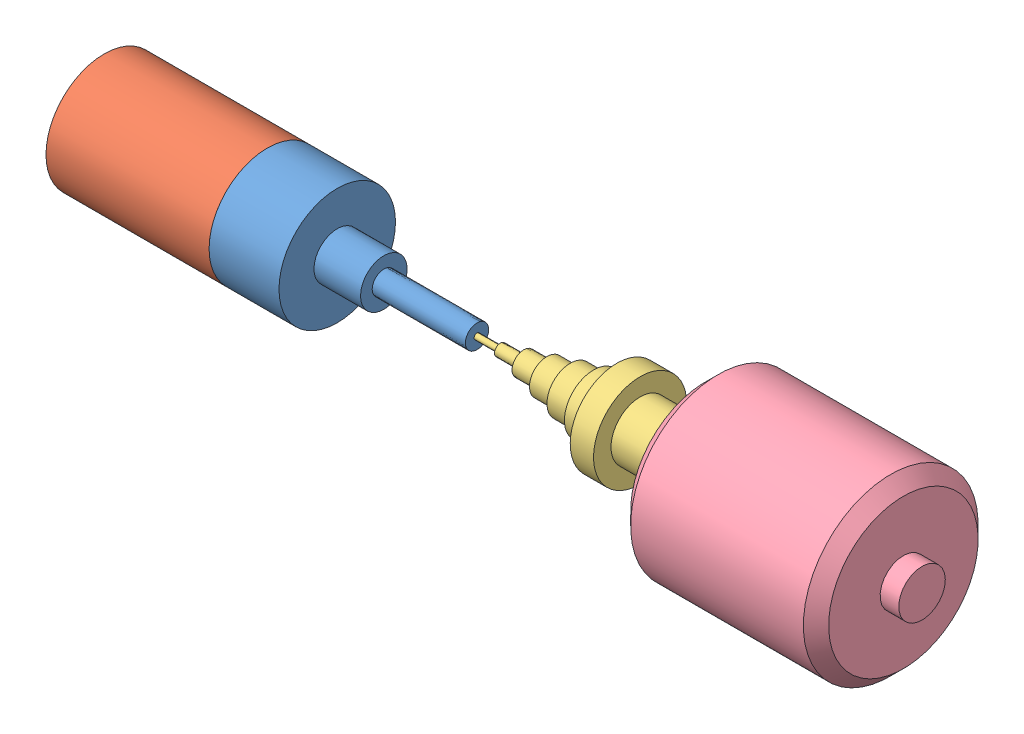
SolidWorks assembly Ensamblaje P55, configuration Predeterminado. Lengths in mm.
Overall size (702 211.51 211.51).
4 component instances, 4 part files, 6 mates.
Components (placement in the parent):
- P55-1: P55 [Predeterminado] at (-114.6088 37.8954 300) size (300 100 100)
- P55.2-1: P55.2 [Predeterminado] at (-284.6088 81.2929 324.8326) x (1 0 0) z (0 -0.496653 0.867949) size (140 100 100)
- P55.3-1: P55.3 [Predeterminado] at (35.3912 37.8954 300) x (-1 0 0) z (0 -0.244449 0.969662) size (180 80 80)
- P55.4-1: P55.4 [Predeterminado] at (225.3912 37.8954 300) x (1 0 0) z (0 0.759315 0.650723) size (202 150 150)
Mates (geometry in assembly coordinates):
- Concéntrica1: concentric anti-aligned: cylinder of P55-1 through (-264.6088 37.8954 300) axis (-1 0 0) radius 10; cylinder of P55.2-1 through (-264.6088 37.8954 300) axis (1 0 0) radius 10
- Coincidente3: coincident anti-aligned: plane of P55-1 through (-264.6088 37.8954 300) normal (-1 0 0); plane of P55.2-1 through (-264.6088 81.2929 324.8326) normal (1 0 0)
- Concéntrica3: concentric anti-aligned: cylinder of P55-1 through (-264.6088 37.8954 300) axis (-1 0 0) radius 10; cylinder of P55.3-1 through (215.3912 37.8954 300) axis (1 0 0) radius 2.5
- Coincidente7: coincident anti-aligned: plane of P55-1 through (35.3912 37.8954 300) normal (1 0 0); plane of P55.3-1 through (35.3912 37.8954 300) normal (-1 0 0)
- Coincidente8: coincident anti-aligned: plane of P55.3-1 through (215.3912 13.6539 293.8888) normal (1 0 0); plane of P55.4-1 through (215.3912 44.4026 292.4068) normal (-1 0 0)
- Concéntrica4: concentric anti-aligned: cylinder of P55.3-1 through (175.3912 37.8954 300) axis (1 0 0) radius 20; cylinder of P55.4-1 through (225.3912 37.8954 300) axis (-1 0 0) radius 20
